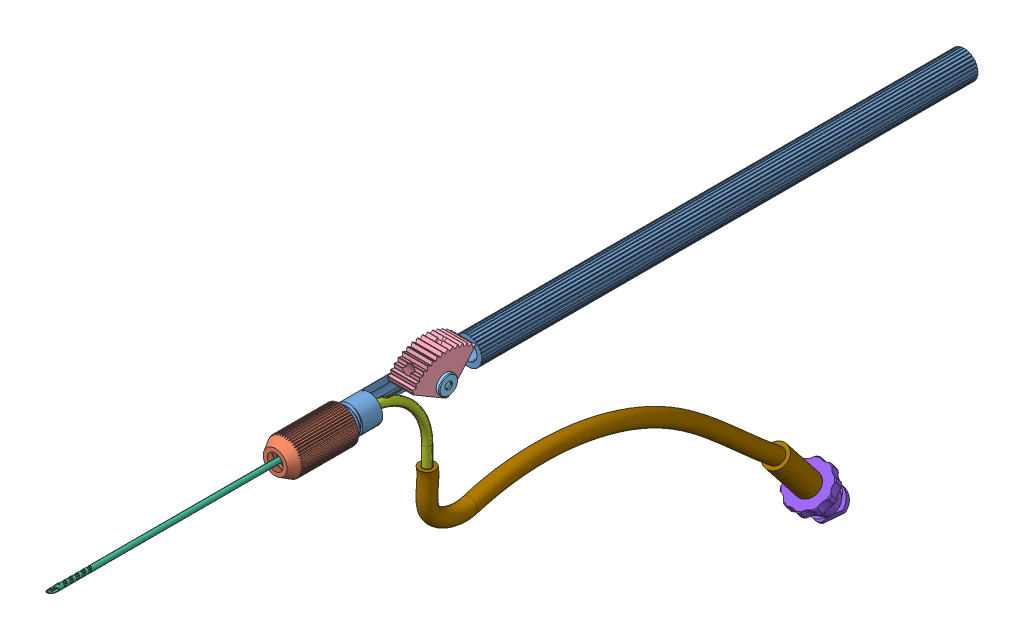
SolidWorks assembly Clinical Tool Assembly, configuration Default. Lengths in mm.
Overall size (15.45 102.39 230.72).
9 component instances, 9 part files, 14 mates.
Components (placement in the parent):
- Handle M7 threads-1: Handle M7 threads [91290A162] at (75.9426 89.8859 210.1647) size (8.08 7.4 171.29)
- 90591A154 M7 collet clamp-1: 90591A154 M7 collet clamp [90591A154] at (75.9426 89.8859 203.2216) x (-0.71098 -0.703212 0) z (0 0 1) size (9 9 17)
- collet-1: collet [Default] at (75.9426 89.8859 189.6173) x (-0.792711 0.609597 0) z (0 0 1) size (5.98 5.98 19)
- wedge v-5 14-Sep-2017_5mm_stainless steel-1: wedge v-5 14-Sep-2017_5mm_stainless steel [Default] at (77.1176 88.6113 182.6997) x (0 0.043667 0.999046) z (-1 0 0) size (31.24 27.17 6.35)
- 90318A101_ULTRA LOW PROFILE TYPE 316 SS SHOULDER SCREW-1: 90318A101_ULTRA LOW PROFILE TYPE 316 SS SHOULDER SCREW [90318A101] at (81.0863 89.8859 174.1647) x (0 0 -1) z (1 0 0) size (4.76 4.76 7.42)
- 135deg CCM V-1 Wrist left-1: 135deg CCM V-1 Wrist left [Default] at (75.9426 89.8859 258.7971) x (0 -1 0) z (0 0 1) size (1.25 1.49 71.09)
- laser suction exit tube-1: laser suction exit tube [Default] at (75.9426 89.8859 194.4658) size (2 21 109.01)
- 51525K315_LIGHTWEIGHT QUICK-TURN TUBE COUPLING-1: 51525K315_LIGHTWEIGHT QUICK-TURN TUBE COUPLING [51525K315] at (75.9426 16.9509 77.7628) x (-0.593973 -0.498011 0.631808) z (0 -0.785357 -0.619043) size (10.87 11.18 9.25)
- suction tube-1: suction tube [Default] at (75.9426 69.8859 174.4658) x (0 0 -1) z (0 1 0) size (100.24 5.8 53.72)
Mates (geometry in assembly coordinates):
- Concentric1: concentric aligned: circle of Handle M7 threads-1; circle of collet-1
- Concentric2: concentric anti-aligned: circle of Handle M7 threads-1; circle of 90591A154 M7 collet clamp-1
- Concentric5: concentric aligned: circle of Handle M7 threads-1; circle of 135deg CCM V-1 Wrist left-1
- Concentric6: concentric aligned: circle of Handle M7 threads-1; circle of laser suction exit tube-1
- Coincident4: coincident anti-aligned: plane of Handle M7 threads-1 through (73.9426 89.8859 210.1647) normal (1 0 0); plane of wedge v-5 14-Sep-2017_5mm_stainless steel-1 through (73.9426 86.2189 173.5509) normal (-1 0 0)
- Concentric7: concentric anti-aligned: circle of Handle M7 threads-1; circle of wedge v-5 14-Sep-2017_5mm_stainless steel-1
- Coincident5: coincident anti-aligned: plane of wedge v-5 14-Sep-2017_5mm_stainless steel-1 through (80.2926 86.2189 173.5509) normal (1 0 0); plane of 90318A101_ULTRA LOW PROFILE TYPE 316 SS SHOULDER SCREW-1 through (80.2926 87.5046 174.1647) normal (-1 0 0)
- Concentric8: concentric aligned: circle of wedge v-5 14-Sep-2017_5mm_stainless steel-1; circle of 90318A101_ULTRA LOW PROFILE TYPE 316 SS SHOULDER SCREW-1
- Parallel1: parallel anti-aligned: plane of Handle M7 threads-1 through (75.9426 89.8859 210.1647) normal (0 1 0); plane of 135deg CCM V-1 Wrist left-1
- Concentric9: concentric aligned: circle of laser suction exit tube-1; circle of suction tube-1
- Coincident6: coincident aligned: circle of laser suction exit tube-1; plane of suction tube-1 through (73.24 70.0693 174.4658) normal (0.135127 0.990828 0)
- Coincident7: coincident anti-aligned: plane of 51525K315_LIGHTWEIGHT QUICK-TURN TUBE COUPLING-1 through (26.2048 26.2846 84.5528) normal (0.364506 0.742916 0.561437); plane of suction tube-1 through (26.1918 24.0774 87.4819) normal (-0.364506 -0.742916 -0.561437)
- Concentric10: concentric aligned: circle of 51525K315_LIGHTWEIGHT QUICK-TURN TUBE COUPLING-1; circle of suction tube-1
- Coincident8: coincident anti-aligned: plane of Handle M7 threads-1 through (75.9426 89.8859 210.1647) normal (1 0 0); plane of suction tube-1
